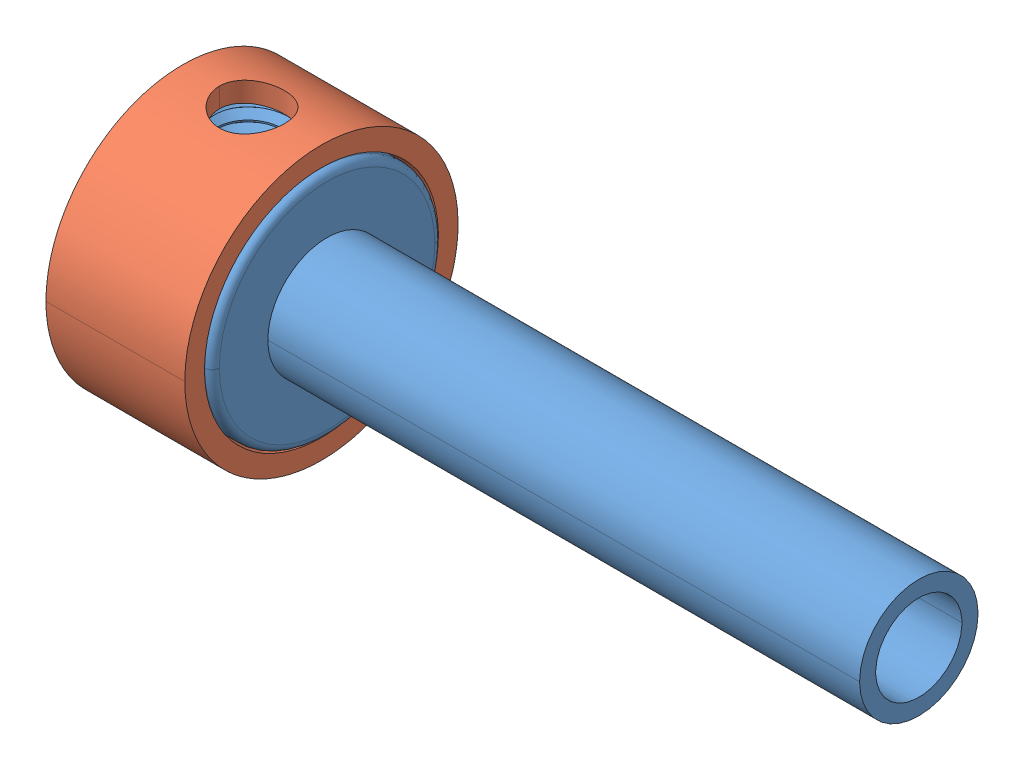
SolidWorks assembly Lite_Hub, configuration Default. Lengths in mm.
Overall size (25.61 15 9.51).
3 component instances, 2 part files, 0 mates.
Components (placement in the parent):
- Lite_Hub.IGS-1: Lite_Hub.IGS [Default] at origin size (25.61 15 9.51)
  - Lite hubs.IGS-1: Lite hubs.IGS [Default] at (-15.2866 1.938 0.1266) size (25.41 15 8.06)
  - Hub Sleeve R2.IGS-1: Hub Sleeve R2.IGS [Default] at (-10.6565 1.938 0.1266) x (0 0 1) z (-1 0 0) size (9.51 9.51 4.84)
